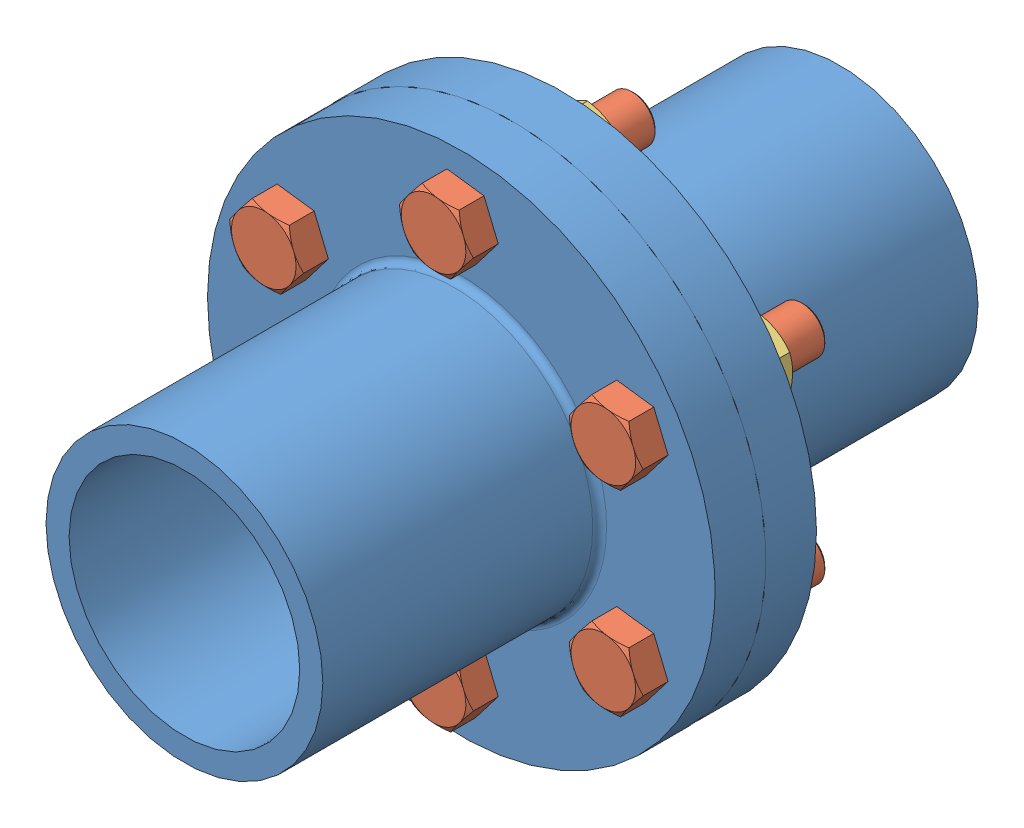
SolidWorks assembly Assem1, configuration Default. Lengths in mm.
Overall size (220 220 284).
14 component instances, 3 part files, 7 mates.
Components (placement in the parent):
- Flange-1: Flange [Default] at (118.7703 161.8584 117.5637) size (220 220 142)
- Flange-2: Flange [Default] at (118.7703 161.8584 117.5637) x (-1 0 0) z (0 0 -1) size (220 220 142)
- Bolt-1: Bolt [Default] at (45.1582 119.3584 139.5637) x (-0.923728 -0.383049 0) z (-0.383049 0.923728 0) size (28 87 32.33)
- Nut-1: Nut [Default] at (45.1582 119.3584 89.5637) x (1 0 0) z (0 1 0) size (28 12 32.33)
- Bolt-2: Bolt [Default] at (45.1582 204.3584 139.5637) x (-0.793594 0.608447 0) z (0.608447 0.793594 0) size (28 87 32.33)
- Bolt-3: Bolt [Default] at (118.7703 246.8584 139.5637) x (0.130134 0.991496 0) z (0.991496 -0.130134 0) size (28 87 32.33)
- Bolt-4: Bolt [Default] at (192.3825 204.3584 139.5637) x (0.923728 0.383049 0) z (0.383049 -0.923728 0) size (28 87 32.33)
- Bolt-5: Bolt [Default] at (192.3825 119.3584 139.5637) x (0.793594 -0.608447 0) z (-0.608447 -0.793594 0) size (28 87 32.33)
- Bolt-6: Bolt [Default] at (118.7703 76.8584 139.5637) x (-0.130134 -0.991496 0) z (-0.991496 0.130134 0) size (28 87 32.33)
- Nut-2: Nut [Default] at (118.7703 76.8584 89.5637) x (0.5 0.866025 0) z (-0.866025 0.5 0) size (28 12 32.33)
- Nut-3: Nut [Default] at (192.3825 119.3584 89.5637) x (-0.5 0.866025 0) z (-0.866025 -0.5 0) size (28 12 32.33)
- Nut-4: Nut [Default] at (192.3825 204.3584 89.5637) x (-1 0 0) z (0 -1 0) size (28 12 32.33)
- Nut-5: Nut [Default] at (118.7703 246.8584 89.5637) x (-0.5 -0.866025 0) z (0.866025 -0.5 0) size (28 12 32.33)
- Nut-6: Nut [Default] at (45.1582 204.3584 89.5637) x (0.5 -0.866025 0) z (0.866025 0.5 0) size (28 12 32.33)
Mates (geometry in assembly coordinates):
- Concentric1: concentric anti-aligned: cylinder of Flange-1 through (118.7703 246.8584 117.5637) axis (0 0 1) radius 10; cylinder of Flange-2 through (118.7703 246.8584 117.5637) axis (0 0 -1) radius 10
- Concentric2: concentric anti-aligned: cylinder of Flange-1 through (118.7703 161.8584 117.5637) axis (0 0 1) radius 50; cylinder of Flange-2 through (118.7703 161.8584 117.5637) axis (0 0 -1) radius 50
- Coincident1: coincident anti-aligned: plane of Flange-1 through (118.7703 161.8584 117.5637) normal (0 0 -1); plane of Flange-2 through (118.7703 161.8584 117.5637) normal (0 0 1)
- Coincident3: coincident aligned: circle of Flange-1; cylinder of Bolt-1 through (45.1582 119.3584 64.5637) axis (0 0 1) radius 10
- Coincident4: coincident anti-aligned: plane of Flange-1 through (118.7703 161.8584 139.5637) normal (0 0 1); plane of Bolt-1 through (45.1582 119.3584 139.5637) normal (0 0 -1)
- Concentric3: concentric anti-aligned: cylinder of Bolt-1 through (45.1582 119.3584 64.5637) axis (0 0 1) radius 10; cylinder of Nut-1 through (45.1582 119.3584 95.5637) axis (0 0 -1) radius 10
- Coincident5: coincident anti-aligned: plane of Flange-2 through (118.7703 161.8584 95.5637) normal (0 0 -1); plane of Nut-1 through (45.1582 119.3584 95.5637) normal (0 0 1)
